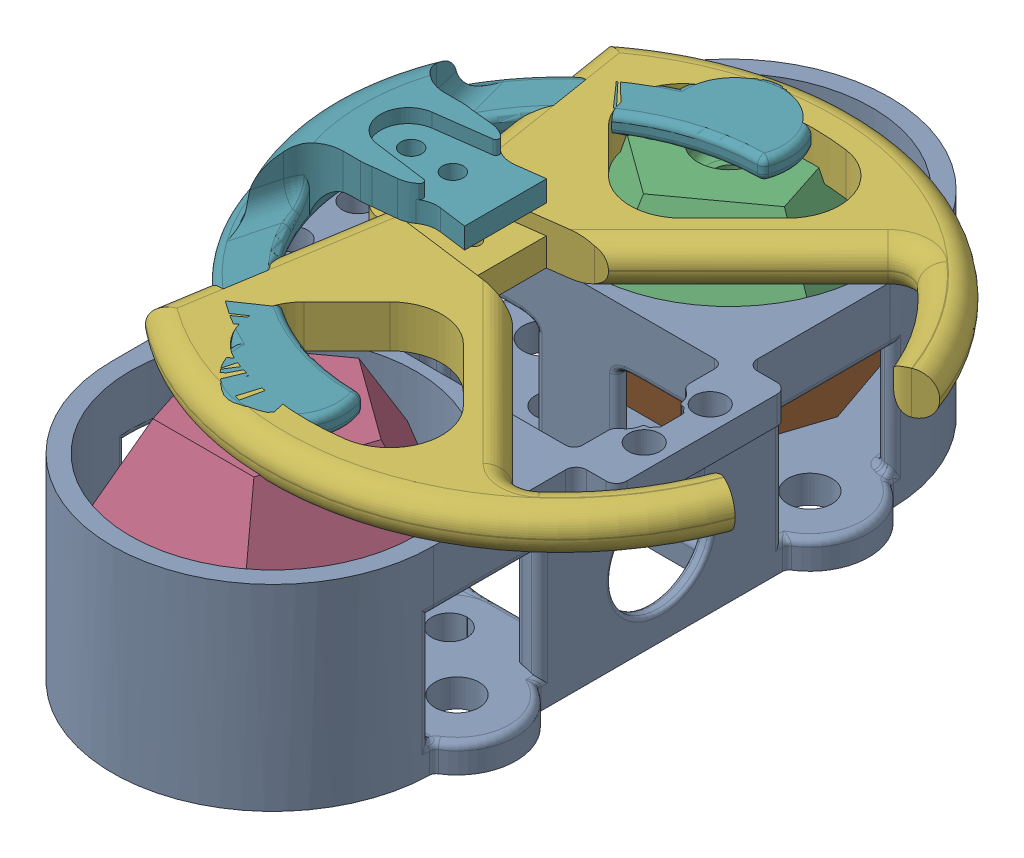
SolidWorks assembly MS25_Marker_DropperAssembly_1-24-25, configuration Default. Lengths in mm.
Overall size (57.8 45.81 118.64).
7 component instances, 5 part files, 12 mates.
Components (placement in the parent):
- MS25_Marker_DropperBody_1-23-25-1: MS25_Marker_DropperBody_1-23-25 [Default] at (2.9563 -4.0363 11.4818) size (57.8 28.3 111.9)
- MS25_Marker_DodecNutSide-1: MS25_Marker_DodecNutSide [Default] at (2.9563 -24.3363 -21.3682) x (0.309017 0 -0.951057) z (0.951057 0 0.309017) size (36.8 15 36.85)
- MS25_Marker_DodecBoltSide-1: MS25_Marker_DodecBoltSide [Default] at (2.9563 5.6637 -21.3682) x (-0.809017 0 0.587785) z (0.587785 0 0.809017) size (36.8 15 36.85)
- MS25_Marker_DodecBoltSide-2: MS25_Marker_DodecBoltSide [Default] at (2.9563 5.6637 44.3318) x (0.809017 0 0.587785) z (0.587785 0 -0.809017) size (36.8 15 36.85)
- MS25_Marker_DodecNutSide-2: MS25_Marker_DodecNutSide [Default] at (2.9563 -24.3363 44.3318) x (-0.309017 0 -0.951057) z (0.951057 0 -0.309017) size (36.8 15 36.85)
- MS25_Marker_D646WPHornAdapter_1-24-25-1: MS25_Marker_D646WPHornAdapter_1-24-25 [Default] at (11.5063 10.1637 11.4818) x (0 0 1) z (1 0 0) (suppressed, hidden)
- MS25_Marker_D646WPHornAdapter_2-2-25-1: MS25_Marker_D646WPHornAdapter_2-2-25 [Default] at (11.5063 10.1637 11.4818) x (0 0 1) z (1 0 0) size (85 13.67 75.49)
Mates (geometry in assembly coordinates):
- Concentric1: concentric anti-aligned: cylinder of MS25_Marker_DodecNutSide-1 through (2.9563 1.9774 -21.3682) axis (0 -1 0) radius 2; cylinder of MS25_Marker_DodecBoltSide-1 through (2.9563 -20.65 -21.3682) axis (0 1 0) radius 2
- Coincident1: coincident anti-aligned: plane of MS25_Marker_DodecNutSide-1 through (2.9563 -9.3363 -21.3682) normal (0 1 0); plane of MS25_Marker_DodecBoltSide-1 through (2.9563 -9.3363 -21.3682) normal (0 -1 0)
- Coincident2: coincident: point of MS25_Marker_DodecNutSide-1; point of MS25_Marker_DodecBoltSide-1
- Coincident3: coincident anti-aligned: plane of MS25_Marker_DropperBody_1-23-25-1 through (2.9563 -24.3363 11.4818) normal (0 1 0); plane of MS25_Marker_DodecNutSide-1 through (2.9563 -24.3363 -21.3682) normal (0 -1 0)
- Concentric2: concentric anti-aligned: cylinder of MS25_Marker_DropperBody_1-23-25-1 through (2.9563 -0.0363 -21.3682) axis (0 -1 0) radius 20.55; cylinder of MS25_Marker_DodecBoltSide-1 through (2.9563 -20.65 -21.3682) axis (0 1 0) radius 2
- Concentric10: concentric aligned: circle of MS25_Marker_D646WPHornAdapter_1-24-25-1
- Coincident4: coincident aligned: plane of MS25_Marker_D646WPHornAdapter_1-24-25-1 through (11.5063 15.1637 11.4818) normal (0 1 0)
- Parallel1: parallel anti-aligned: plane of MS25_Marker_DropperBody_1-23-25-1 through (2.9563 -0.0363 22.2318) normal (0 0 -1); plane of MS25_Marker_D646WPHornAdapter_1-24-25-1 through (11.5063 15.1637 18.7758) normal (0 0 1)
- Parallel4: parallel: plane of MS25_Marker_DropperBody_1-23-25-1 through (2.9563 -0.0363 0.7318) normal (0 0 1); line of MS25_Marker_DodecBoltSide-1 through (-4.3091 5.6637 -31.3682) axis (1 0 0)
- Coincident5: coincident aligned: plane of MS25_Marker_D646WPHornAdapter_2-2-25-1 through (3.141 -10.491 9.9241) normal (0 1 0)
- Concentric11: concentric aligned: cylinder of MS25_Marker_D646WPHornAdapter_2-2-25-1 through (24.9855 -18.491 11.4818) axis (0 1 0) radius 28.7939
- Parallel5: parallel anti-aligned: plane of MS25_Marker_DropperBody_1-23-25-1 through (2.9563 -0.0363 22.2318) normal (0 0 -1); plane of MS25_Marker_D646WPHornAdapter_2-2-25-1 through (11.5063 17.1637 18.7758) normal (0 0 1)
